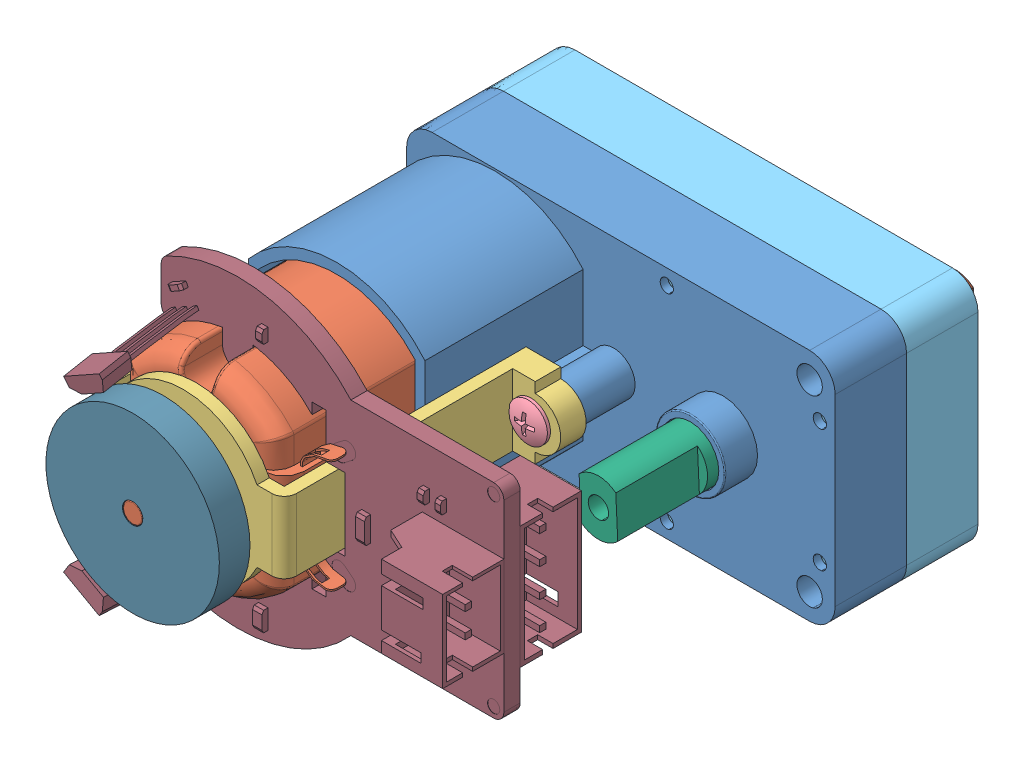
SolidWorks assembly TT_ANGLE_MOTOR_WITH_ENCODER, configuration По умолчанию. Lengths in mm.
Overall size (49.84 29.86 58.37).
17 component instances, 15 part files, 0 mates.
Components (placement in the parent):
- 1-1: 1 [По умолчанию] at (18.7579 -8.136 0) size (47.1 23 22.5)
- 2-1: 2 [По умолчанию] at (-11.2666 2.0594 10.6) size (20.08 20 41.9)
- 3-1: 3 [По умолчанию] at (-11.2666 2.0594 36.3) x (-1 0 0) z (0 0 1) size (29.11 16 24.9)
- 4-1: 4 [По умолчанию] at (-22.9166 2.0594 5.4) x (0 0 -1) z (1 0 0) size (10.55 3.86 3.98)
- 4-2: 4 [По умолчанию] at (0.3834 2.0594 5.4) x (0 0 -1) z (1 0 0) size (10.55 3.86 3.98)
- 5-1: 5 [По умолчанию] at (18.7579 -8.136 0) x (-1 0 0) z (0 0 -1) size (42 23 15.3)
- 6-1: 6 [По умолчанию] at (11.0834 2.0594 7) x (0.998872 0.047482 0) z (0 0 1) size (5.4 5.4 29.2)
- 7-1: 7 [По умолчанию] at (-0.3166 2.0594 3.6) x (-0.926164 -0.377122 0) z (0 0 -1) size (18.6 18.6 4.5)
- 8-1: 8 [По умолчанию] at (-0.3166 2.0594 -8.2) x (-0.150609 -0.988593 0) z (0 0 1) size (2 2 14.4)
- 9-1: 9 [По умолчанию] at (11.0834 2.0594 1.1) x (-0.822827 -0.568292 0) z (0 0 -1) size (18.6 18.6 4.5)
- 10-1: 10 [По умолчанию] at (-0.3166 2.0594 -1.4) x (-0.973048 -0.230602 0) z (0 0 -1) size (14.65 14.7 4.5)
- 11-1: 11 [По умолчанию] at (11.0834 2.0594 -3.1) x (-0.998872 -0.047482 0) z (0 0 -1) size (14.65 14.7 12.7)
- 12-1: 12 [По умолчанию] at (-8.3166 -6.9406 7) x (0 0 1) z (-1 0 0) size (14.6 4.05 4.15)
- 12-2: 12 [По умолчанию] at (-8.3166 11.0594 7) x (0 0 1) z (-1 0 0) size (14.6 4.05 4.15)
- 13-1: 13 [По умолчанию] at (-11.2666 2.0594 30.6) x (0 1 0) z (0 0 1) size (29.86 33.59 17.97)
- 14-1: 14 [По умолчанию] at (-11.2666 2.0594 39.5) x (0.099647 -0.995023 0) z (0 0 1) size (17 17 3)
- 15-1: 15 [По умолчанию] at origin size (2.72 25.67 3.81)
